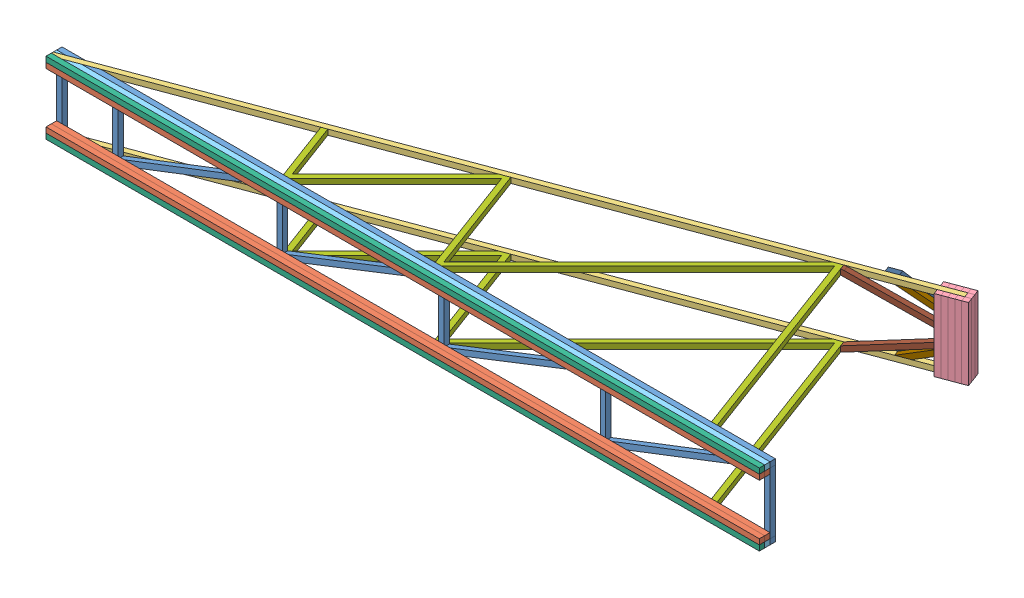
SolidWorks assembly boomAssembly2_1, configuration Default. Lengths in mm.
Overall size (423.17 42.7 155.97).
28 component instances, 12 part files, 91 mates.
Components (placement in the parent):
- cross brace compression-3: cross brace compression [Default] at (-109.2004 207.2528 347.8228) size (423.18 42.7 3.17)
- Part1-1: Part1 [Default] at (-109.2004 207.2528 354.1728) size (423.18 36.35 3.17)
- tension members-3: tension members [Default] at (269.1249 227.7278 350.9978) x (-1 0 0) z (0 0 1) size (396.18 3.18 148.71)
- tension members-4: tension members [Default] at (269.1249 267.2528 350.9978) x (-1 0 0) z (0 0 1) size (396.18 3.18 148.71)
- jHookMount-1: jHookMount [Default] at (264.7186 215.9028 209.7497) x (0.936777 0 -0.349926) z (0 1 0) size (3.17 3.17 42.7)
- jHookMount-2: jHookMount [Default] at (266.9407 215.9028 215.6982) x (0.936777 0 -0.349926) z (0 1 0) size (3.17 3.17 42.7)
- Part1^boomAssembly2_1-1: Part1^boomAssembly2_1 [Default] at origin (virtual)
- Part2^boomAssembly2_1-1: Part2^boomAssembly2_1 [Default] at (269.1249 258.6028 350.9978) x (1 0 0) z (0 1 0) size (423.17 3.17 3.17) (virtual)
- Part1-2: Part1 [Default] at (-109.2004 207.2528 357.3478) size (423.18 36.35 3.17)
- Part3^boomAssembly2_1-1: Part3^boomAssembly2_1 [Default] at (-127.3754 207.2528 357.3478) x (0 0 1) z (-1 0 0) size (3.17 42.7 423.18) (virtual)
- Part4^boomAssembly2_1-1: Part4^boomAssembly2_1 [Default] at (269.1249 258.6028 350.9978) x (1 0 0) z (0 1 0) size (270.59 119.85 3.17) (virtual)
- Part2^boomAssembly2_1-2: Part2^boomAssembly2_1 [Default] at (269.1249 219.0778 350.9978) x (1 0 0) z (0 1 0) size (423.17 3.17 3.17) (virtual)
- Part4^boomAssembly2_1-2: Part4^boomAssembly2_1 [Default] at (269.1249 219.0778 350.9978) x (1 0 0) z (0 1 0) size (270.59 119.85 3.17) (virtual)
- jHookMount-8: jHookMount [Default] at (261.7444 215.9028 210.8607) x (0.936777 0 -0.349926) z (0 1 0) size (3.17 3.17 42.7)
- jHookMount-9: jHookMount [Default] at (265.8296 215.9028 212.724) x (-0.936777 0 0.349926) z (0 1 0) size (3.17 3.17 42.7)
- jHookMount-10: jHookMount [Default] at (258.7701 215.9028 211.9717) x (0.936777 0 -0.349926) z (0 1 0) size (3.17 3.17 42.7)
- jHookMount-11: jHookMount [Default] at (260.9921 215.9028 217.9203) x (0.936777 0 -0.349926) z (0 1 0) size (3.17 3.17 42.7)
- Part5^boomAssembly2_1-1: Part5^boomAssembly2_1 [Default] at (267.6929 215.9028 208.6387) x (0 -1 0) z (0.936777 0 -0.349926) size (36.35 3.17 3.17) (virtual)
- Part5^boomAssembly2_1-2: Part5^boomAssembly2_1 [Default] at (264.7186 215.9028 209.7497) x (0 -1 0) z (0.936777 0 -0.349926) size (36.35 3.17 3.17) (virtual)
- Part5^boomAssembly2_1-3: Part5^boomAssembly2_1 [Default] at (261.7444 215.9028 210.8607) x (0 -1 0) z (0.936777 0 -0.349926) size (36.35 3.17 3.17) (virtual)
- jHookMount-12: jHookMount [Default] at (268.8039 215.9028 211.6129) x (0.936777 0 -0.349926) z (0 1 0) size (3.17 3.17 42.7)
- jHookMount-13: jHookMount [Default] at (267.6929 215.9028 208.6387) x (0.936777 0 -0.349926) z (0 1 0) size (3.17 3.17 42.7)
- jHookMount-14: jHookMount [Default] at (269.9119 215.9028 214.5791) x (0.936777 0 -0.349926) z (0 1 0) size (3.17 3.17 42.7)
- Part6^boomAssembly2_1-1: Part6^boomAssembly2_1 [Default] at (222.2837 227.7278 225.6009) x (0.936777 0 -0.349926) z (-0.349926 0 -0.936777) size (22.84 36.35 3.17) (virtual)
- jHookMount-16: jHookMount [Default] at (258.0179 215.9028 219.0313) x (0.936777 0 -0.349926) z (0 1 0) size (3.17 3.17 42.7)
- jHookMount-17: jHookMount [Default] at (255.7958 215.9028 213.0827) x (0.936777 0 -0.349926) z (0 1 0) size (3.17 3.17 42.7)
- Part7^boomAssembly2_1-1: Part7^boomAssembly2_1 [Default] at (222.2837 227.7278 225.6009) x (0.936777 0 -0.349926) z (-0.349926 0 -0.936777) size (25.51 42.7 3.17) (virtual)
- Part9^boomAssembly2_1-1: Part9^boomAssembly2_1 [Default] at (223.3948 267.2528 228.5752) x (-0.936777 0 0.349926) z (0.349926 0 0.936777) size (43.13 42.7 3.17) (virtual)
Mates (geometry in assembly coordinates):
- Coincident4: coincident: plane of cross brace compression-3 through (-127.3754 207.2528 350.9978) normal (-1 0 0); plane of Part1-1 through (-127.3754 207.2528 357.3478) normal (-1 0 0)
- Coincident5: coincident: plane of cross brace compression-3 through (-109.2004 207.2528 354.1728) normal (0 0 1); plane of Part1-1 through (-109.2004 207.2528 354.1728) normal (0 0 -1)
- Coincident7: coincident: plane of Part1-1 through (-109.2004 207.2528 357.3478) normal (0 0 1); plane of tension members-3 through (291.79 227.7278 357.3478) normal (0 0 1)
- Coincident8: coincident: plane of cross brace compression-3 through (-107.5644 219.0778 352.2026) normal (-0.349926 0 -0.936777); plane of tension members-3 through (223.3948 176.3778 228.5752) normal (0.349926 0 0.936777)
- Coincident9: coincident: plane of Part1-1 through (-109.2004 219.0778 357.3478) normal (0 -1 0); plane of tension members-3 through (291.79 219.0778 350.9978) normal (0 1 0)
- Coincident10: coincident: plane of cross brace compression-3 through (-108.6754 255.4278 349.2284) normal (0.349926 0 0.936777); plane of tension members-4 through (222.2837 215.9028 225.6009) normal (-0.349926 0 -0.936777)
- Coincident11: coincident: plane of Part1-1 through (-109.2004 207.2528 357.3478) normal (0 0 1); plane of tension members-4 through (291.79 267.2528 357.3478) normal (0 0 1)
- Coincident12: coincident: plane of cross brace compression-3 through (-131.8656 258.6028 347.8228) normal (0 1 0); plane of tension members-4 through (291.79 258.6028 350.9978) normal (0 1 0)
- Coincident13: coincident: plane of cross brace compression-3 through (-131.8656 219.0778 347.8228) normal (0 1 0); plane of Part1-1 through (-109.2004 219.0778 357.3478) normal (0 -1 0)
- Coincident14: coincident: plane of tension members-3 through (222.2837 176.3778 225.6009) normal (-0.349926 0 -0.936777); plane of jHookMount-1 through (264.7186 258.6028 209.7497) normal (0.349926 0 0.936777)
- Coincident15: coincident: plane of tension members-4 through (291.79 258.6028 350.9978) normal (0 1 0); plane of jHookMount-1 through (264.7186 258.6028 209.7497) normal (0 1 0)
- Coincident17: coincident: plane of tension members-3 through (223.3948 176.3778 228.5752) normal (0.349926 0 0.936777); plane of jHookMount-2 through (265.8296 258.6028 212.724) normal (-0.349926 0 -0.936777)
- Coincident19: coincident: plane of tension members-3 through (291.79 215.9028 350.9978) normal (0 -1 0); plane of jHookMount-2 through (266.9407 215.9028 215.6982) normal (0 -1 0)
- InPlace1: in place: plane of tension members-4 through (291.79 258.6028 350.9978) normal (0 1 0); plane of ? through (0 258.6028 0) normal (0 1 0); moOrthogonalPlaneRef_w of tension members-4 through (291.79 258.6028 350.9978) normal (0 1 0); plane of ? through (0 258.6028 0) normal (0 0 -1); plane of tension members-4 through (291.79 258.6028 350.9978) normal (0 1 0); plane of ? through (0 258.6028 0) normal (1 0 0); plane of tension members-4 through (291.79 258.6028 350.9978) normal (0 1 0); unknown of ?
- Coincident20: coincident: plane of tension members-4; plane of Part2^boomAssembly2_1-1
- Coincident21: coincident: moOrthogonalPlaneRef_w of tension members-4 through (269.1249 258.6028 350.9978) normal (0 0 -1); plane of Part2^boomAssembly2_1-1 through (269.1249 258.6028 350.9978) normal (0 0 -1)
- Coincident22: coincident: moOrthogonalPlaneRef_w of tension members-4 through (269.1249 258.6028 350.9978) normal (-1 0 0); plane of Part2^boomAssembly2_1-1 through (269.1249 258.6028 350.9978) normal (1 0 0)
- Coincident23: coincident: plane of Part1-1 through (-109.2004 222.2528 357.3478) normal (0 1 0); plane of Part1-2 through (-109.2004 222.2528 360.5228) normal (0 1 0)
- Coincident24: coincident: plane of Part1-1 through (-109.2004 207.2528 357.3478) normal (0 0 1); plane of Part1-2 through (-109.2004 207.2528 357.3478) normal (0 0 -1)
- Coincident25: coincident: plane of cross brace compression-3 through (-127.3754 207.2528 350.9978) normal (-1 0 0); plane of Part1-2 through (-127.3754 207.2528 360.5228) normal (-1 0 0)
- InPlace2: in place: plane of Part1-2 through (-127.3754 207.2528 360.5228) normal (-1 0 0); plane of ? through (-127.3754 0 0) normal (-1 0 0); plane of Part1-2 through (-127.3754 207.2528 360.5228) normal (-1 0 0); plane of ? through (-127.3754 0 0) normal (0 1 0); plane of Part1-2 through (-127.3754 207.2528 360.5228) normal (-1 0 0); plane of ? through (-127.3754 0 0) normal (0 0 1); plane of Part1-2 through (-127.3754 207.2528 360.5228) normal (-1 0 0); unknown of Part3^boomAssembly2_1-1
- Coincident26: coincident: plane of Part1-2; plane of Part3^boomAssembly2_1-1
- Coincident27: coincident: moOrthogonalPlaneRef_w of Part1-2 through (-127.3754 207.2528 357.3478) normal (0 1 0); plane of Part3^boomAssembly2_1-1 through (-127.3754 207.2528 357.3478) normal (0 1 0)
- Coincident28: coincident: moOrthogonalPlaneRef_w of Part1-2 through (-127.3754 207.2528 357.3478) normal (0 0 -1); plane of Part3^boomAssembly2_1-1 through (-127.3754 207.2528 357.3478) normal (0 0 1)
- InPlace3: in place: plane of tension members-4 through (291.79 258.6028 350.9978) normal (0 1 0); plane of ? through (0 258.6028 0) normal (0 1 0); plane of tension members-4 through (291.79 258.6028 350.9978) normal (0 1 0); plane of ? through (0 258.6028 0) normal (0 0 -1); plane of tension members-4 through (291.79 258.6028 350.9978) normal (0 1 0); plane of ? through (0 258.6028 0) normal (1 0 0); plane of tension members-4 through (291.79 258.6028 350.9978) normal (0 1 0); unknown of ?
- Coincident29: coincident: plane of tension members-4; plane of Part4^boomAssembly2_1-1
- Coincident30: coincident: moOrthogonalPlaneRef_w of tension members-4 through (269.1249 258.6028 350.9978) normal (0 0 -1); plane of Part4^boomAssembly2_1-1 through (269.1249 258.6028 350.9978) normal (0 0 -1)
- Coincident31: coincident: moOrthogonalPlaneRef_w of tension members-4 through (269.1249 258.6028 350.9978) normal (-1 0 0); plane of Part4^boomAssembly2_1-1 through (269.1249 258.6028 350.9978) normal (1 0 0)
- Coincident32: coincident: plane of tension members-4 through (314.534 267.2528 334.0356) normal (0.936777 0 -0.349926); plane of jHookMount-1 through (267.6929 258.6028 208.6387) normal (0.936777 0 -0.349926)
- Coincident33: coincident: plane of tension members-4 through (314.534 267.2528 334.0356) normal (0.936777 0 -0.349926); plane of jHookMount-2 through (269.9149 258.6028 214.5872) normal (0.936777 0 -0.349926)
- Coincident34: coincident: plane of tension members-4 through (223.3948 215.9028 228.5752) normal (0.349926 0 0.936777); plane of jHookMount-11 through (259.8811 258.6028 214.946) normal (-0.349926 0 -0.936777)
- Coincident35: coincident: plane of tension members-4 through (223.3948 215.9028 228.5752) normal (0.349926 0 0.936777); plane of jHookMount-9 through (265.8296 258.6028 212.724) normal (-0.349926 0 -0.936777)
- Coincident36: coincident: plane of tension members-3 through (291.79 215.9028 350.9978) normal (0 -1 0); plane of jHookMount-9 through (265.8296 215.9028 212.724) normal (0 -1 0)
- Coincident37: coincident: plane of tension members-3 through (291.79 215.9028 350.9978) normal (0 -1 0); plane of jHookMount-11 through (260.9921 215.9028 217.9203) normal (0 -1 0)
- Coincident38: coincident: plane of tension members-3 through (222.2837 176.3778 225.6009) normal (-0.349926 0 -0.936777); plane of jHookMount-8 through (261.7444 258.6028 210.8607) normal (0.349926 0 0.936777)
- Coincident39: coincident: plane of tension members-3 through (222.2837 176.3778 225.6009) normal (-0.349926 0 -0.936777); plane of jHookMount-10 through (258.7701 258.6028 211.9717) normal (0.349926 0 0.936777)
- Coincident40: coincident: plane of tension members-3 through (291.79 215.9028 350.9978) normal (0 -1 0); plane of jHookMount-8 through (261.7444 215.9028 210.8607) normal (0 -1 0)
- Coincident41: coincident: plane of tension members-3 through (291.79 215.9028 350.9978) normal (0 -1 0); plane of jHookMount-10 through (258.7701 215.9028 211.9717) normal (0 -1 0)
- Coincident42: coincident: plane of jHookMount-1 through (264.7186 258.6028 209.7497) normal (-0.936777 0 0.349926); plane of jHookMount-8 through (264.7186 258.6028 209.7497) normal (0.936777 0 -0.349926)
- Coincident43: coincident: plane of jHookMount-8 through (261.7444 258.6028 210.8607) normal (-0.936777 0 0.349926); plane of jHookMount-10 through (261.7444 258.6028 210.8607) normal (0.936777 0 -0.349926)
- Coincident44: coincident: plane of jHookMount-2 through (266.9407 258.6028 215.6982) normal (-0.936777 0 0.349926); plane of jHookMount-9 through (265.8296 258.6028 212.724) normal (0.936777 0 -0.349926)
- Coincident45: coincident: plane of jHookMount-9 through (262.8554 258.6028 213.835) normal (-0.936777 0 0.349926); plane of jHookMount-11 through (263.9664 258.6028 216.8092) normal (0.936777 0 -0.349926)
- InPlace4: in place: plane of jHookMount-8 through (264.7186 258.6028 209.7497) normal (0.936777 0 -0.349926); plane of ? through (163.5476 0 -61.092) normal (0.936777 0 -0.349926); plane of jHookMount-8 through (264.7186 258.6028 209.7497) normal (0.936777 0 -0.349926); plane of ? through (163.5476 0 -61.092) normal (0 1 0); plane of jHookMount-8 through (264.7186 258.6028 209.7497) normal (0.936777 0 -0.349926); plane of ? through (163.5476 0 -61.092) normal (-0.349926 0 -0.936777); plane of jHookMount-1 through (267.6929 258.6028 208.6387) normal (0.936777 0 -0.349926); unknown of Part5^boomAssembly2_1-1
- Coincident46: coincident: plane of jHookMount-1; plane of Part5^boomAssembly2_1-1
- Coincident47: coincident: moOrthogonalPlaneRef_w of jHookMount-1 through (267.6929 215.9028 208.6387) normal (-0.349926 0 -0.936777); plane of Part5^boomAssembly2_1-1 through (267.6929 215.9028 208.6387) normal (-0.349926 0 -0.936777)
- Coincident48: coincident: moOrthogonalPlaneRef_w of jHookMount-1 through (267.6929 215.9028 208.6387) normal (0 1 0); plane of Part5^boomAssembly2_1-1 through (267.6929 215.9028 208.6387) normal (0 -1 0)
- Coincident49: coincident: plane of tension members-4 through (291.79 255.4278 350.9978) normal (0 -1 0); plane of Part5^boomAssembly2_1-2 through (261.7444 255.4278 210.8607) normal (0 1 0)
- Coincident50: coincident: plane of Part5^boomAssembly2_1-1 through (264.7186 215.9028 209.7497) normal (-0.936777 0 0.349926); plane of Part5^boomAssembly2_1-2 through (264.7186 215.9028 209.7497) normal (0.936777 0 -0.349926)
- Coincident51: coincident: plane of jHookMount-8 through (261.7444 258.6028 210.8607) normal (0.349926 0 0.936777); plane of Part5^boomAssembly2_1-2 through (261.7444 255.4278 210.8607) normal (-0.349926 0 -0.936777)
- Coincident52: coincident: plane of jHookMount-10 through (258.7701 258.6028 211.9717) normal (0.349926 0 0.936777); plane of Part5^boomAssembly2_1-3 through (258.7701 255.4278 211.9717) normal (-0.349926 0 -0.936777)
- Coincident53: coincident: plane of tension members-4 through (291.79 255.4278 350.9978) normal (0 -1 0); plane of Part5^boomAssembly2_1-3 through (258.7701 255.4278 211.9717) normal (0 1 0)
- Coincident54: coincident: plane of Part5^boomAssembly2_1-2 through (261.7444 215.9028 210.8607) normal (-0.936777 0 0.349926); plane of Part5^boomAssembly2_1-3 through (261.7444 215.9028 210.8607) normal (0.936777 0 -0.349926)
- Coincident55: coincident: plane of jHookMount-2 through (266.9407 258.6028 215.6982) normal (0.936777 0 -0.349926); plane of ? through (265.8296 212.7278 212.724) normal (-0.936777 0 0.349926)
- Coincident56: coincident: plane of tension members-3 through (223.3948 176.3778 228.5752) normal (0.349926 0 0.936777); plane of ? through (265.8296 252.2528 212.724) normal (-0.349926 0 -0.936777)
- Coincident57: coincident: plane of jHookMount-2 through (263.9664 215.9028 216.8092) normal (0 -1 0); plane of ? through (265.8296 215.9028 212.724) normal (0 -1 0)
- Coincident58: coincident: plane of Part5^boomAssembly2_1-1 through (267.6929 215.9028 208.6387) normal (0.936777 0 -0.349926); plane of ? through (267.6929 215.9028 208.6387) normal (-0.936777 0 0.349926)
- Coincident59: coincident: plane of tension members-3 through (291.79 219.0778 350.9978) normal (0 1 0); plane of ? through (267.6929 219.0778 208.6387) normal (0 -1 0)
- Coincident60: coincident: plane of tension members-3 through (222.2837 176.3778 225.6009) normal (-0.349926 0 -0.936777); plane of ? through (267.6929 255.4278 208.6387) normal (-0.349926 0 -0.936777)
- Coincident61: coincident: plane of tension members-3 through (291.79 215.9028 350.9978) normal (0 -1 0); plane of jHookMount-12 through (268.8039 215.9028 211.6129) normal (0 -1 0)
- Coincident62: coincident: plane of Part5^boomAssembly2_1-1 through (267.6929 215.9028 208.6387) normal (0.936777 0 -0.349926); plane of jHookMount-12 through (268.8039 258.6028 211.6129) normal (-0.936777 0 0.349926)
- Coincident63: coincident: plane of tension members-3 through (222.2837 176.3778 225.6009) normal (-0.349926 0 -0.936777); plane of jHookMount-12 through (267.6929 258.6028 208.6387) normal (-0.349926 0 -0.936777)
- Coincident64: coincident: plane of jHookMount-12 through (271.7782 258.6028 210.5019) normal (0.936777 0 -0.349926); plane of jHookMount-13 through (270.6672 258.6028 207.5277) normal (0.936777 0 -0.349926)
- Coincident65: coincident: plane of jHookMount-12 through (271.7782 258.6028 210.5019) normal (0.936777 0 -0.349926); plane of jHookMount-14 through (272.8862 258.6028 213.4681) normal (0.936777 0 -0.349926)
- Coincident66: coincident: plane of jHookMount-12 through (268.8039 215.9028 211.6129) normal (0 -1 0); plane of jHookMount-13 through (267.6929 215.9028 208.6387) normal (0 -1 0)
- Coincident67: coincident: plane of jHookMount-12 through (268.8039 215.9028 211.6129) normal (0 -1 0); plane of jHookMount-14 through (269.9119 215.9028 214.5791) normal (0 -1 0)
- Coincident68: coincident: plane of jHookMount-12 through (267.6929 258.6028 208.6387) normal (-0.349926 0 -0.936777); plane of jHookMount-13 through (267.6929 258.6028 208.6387) normal (0.349926 0 0.936777)
- InPlace5: in place: plane of tension members-3 through (222.2837 176.3778 225.6009) normal (-0.349926 0 -0.936777); plane of ? through (101.171 0 270.8417) normal (-0.349926 0 -0.936777); plane of tension members-3 through (222.2837 176.3778 225.6009) normal (-0.349926 0 -0.936777); plane of ? through (101.171 0 270.8417) normal (0 1 0); plane of tension members-3 through (222.2837 176.3778 225.6009) normal (-0.349926 0 -0.936777); plane of ? through (101.171 0 270.8417) normal (-0.936777 0 0.349926); plane of tension members-3 through (222.2837 176.3778 225.6009) normal (-0.349926 0 -0.936777); unknown of ?
- Coincident69: coincident: plane of tension members-3; plane of Part6^boomAssembly2_1-1
- Coincident70: coincident: moOrthogonalPlaneRef_w of tension members-3 through (222.2837 227.7278 225.6009) normal (0 -1 0); plane of Part6^boomAssembly2_1-1 through (222.2837 227.7278 225.6009) normal (0 -1 0)
- Coincident71: coincident: moOrthogonalPlaneRef_w of tension members-3 through (222.2837 227.7278 225.6009) normal (-0.936777 0 0.349926); plane of Part6^boomAssembly2_1-1 through (222.2837 227.7278 225.6009) normal (0.936777 0 -0.349926)
- Coincident72: coincident: plane of Part6^boomAssembly2_1-1 through (223.3948 215.9028 228.5752) normal (0.349926 0 0.936777); plane of jHookMount-16 through (256.9068 258.6028 216.057) normal (-0.349926 0 -0.936777)
- Coincident73: coincident: plane of tension members-3 through (222.2837 176.3778 225.6009) normal (-0.349926 0 -0.936777); plane of jHookMount-17 through (255.7958 258.6028 213.0827) normal (0.349926 0 0.936777)
- Coincident74: coincident: plane of jHookMount-11 through (260.9921 215.9028 217.9203) normal (0 -1 0); plane of jHookMount-16 through (258.0179 215.9028 219.0313) normal (0 -1 0)
- Coincident75: coincident: plane of tension members-3 through (291.79 215.9028 350.9978) normal (0 -1 0); plane of jHookMount-17 through (255.7958 215.9028 213.0827) normal (0 -1 0)
- Coincident76: coincident: plane of jHookMount-10 through (258.7701 258.6028 211.9717) normal (-0.936777 0 0.349926); plane of jHookMount-17 through (258.7701 258.6028 211.9717) normal (0.936777 0 -0.349926)
- Coincident77: coincident: plane of jHookMount-11 through (260.9921 258.6028 217.9203) normal (-0.936777 0 0.349926); plane of jHookMount-16 through (260.9921 258.6028 217.9203) normal (0.936777 0 -0.349926)
- InPlace6: in place: plane of tension members-3 through (222.2837 176.3778 225.6009) normal (-0.349926 0 -0.936777); plane of ? through (101.171 0 270.8417) normal (-0.349926 0 -0.936777); plane of tension members-3 through (222.2837 176.3778 225.6009) normal (-0.349926 0 -0.936777); plane of ? through (101.171 0 270.8417) normal (0 1 0); plane of tension members-3 through (222.2837 176.3778 225.6009) normal (-0.349926 0 -0.936777); plane of ? through (101.171 0 270.8417) normal (-0.936777 0 0.349926); plane of tension members-3 through (222.2837 176.3778 225.6009) normal (-0.349926 0 -0.936777); unknown of ?
- Coincident78: coincident: plane of tension members-3; plane of Part7^boomAssembly2_1-1
- Coincident79: coincident: moOrthogonalPlaneRef_w of tension members-3 through (222.2837 227.7278 225.6009) normal (0 -1 0); plane of Part7^boomAssembly2_1-1 through (222.2837 227.7278 225.6009) normal (0 -1 0)
- Coincident80: coincident: moOrthogonalPlaneRef_w of tension members-3 through (222.2837 227.7278 225.6009) normal (-0.936777 0 0.349926); plane of Part7^boomAssembly2_1-1 through (222.2837 227.7278 225.6009) normal (0.936777 0 -0.349926)
- Coincident81: coincident: plane of jHookMount-16 through (258.0179 258.6028 219.0313) normal (-0.936777 0 0.349926); plane of ? through (256.9068 229.7528 216.057) normal (0.936777 0 -0.349926)
- Coincident82: coincident: plane of tension members-3 through (291.79 215.9028 350.9978) normal (0 -1 0); plane of ? through (233.0113 215.9028 224.983) normal (0 -1 0)
- Coincident83: coincident: plane of tension members-3 through (223.3948 176.3778 228.5752) normal (0.349926 0 0.936777); plane of ? through (223.3948 227.7278 228.5752) normal (-0.349926 0 -0.936777)
- InPlace7: in place: plane of tension members-4 through (223.3948 215.9028 228.5752) normal (0.349926 0 0.936777); plane of ? through (102.282 0 273.816) normal (0.349926 0 0.936777); plane of tension members-4 through (223.3948 215.9028 228.5752) normal (0.349926 0 0.936777); plane of ? through (102.282 0 273.816) normal (0 1 0); plane of tension members-4 through (223.3948 215.9028 228.5752) normal (0.349926 0 0.936777); plane of ? through (102.282 0 273.816) normal (0.936777 0 -0.349926); plane of tension members-4 through (223.3948 215.9028 228.5752) normal (0.349926 0 0.936777); unknown of Part9^boomAssembly2_1-1
- Coincident84: coincident: plane of tension members-4; plane of ?
- Coincident85: coincident: moOrthogonalPlaneRef_w of tension members-4 through (223.3948 267.2528 228.5752) normal (0 -1 0); plane of Part9^boomAssembly2_1-1 through (223.3948 267.2528 228.5752) normal (0 -1 0)
- Coincident86: coincident: moOrthogonalPlaneRef_w of tension members-4 through (223.3948 267.2528 228.5752) normal (0.936777 0 -0.349926); plane of Part9^boomAssembly2_1-1 through (223.3948 267.2528 228.5752) normal (-0.936777 0 0.349926)
- InPlace8: in place: plane of tension members-4 through (223.3948 215.9028 228.5752) normal (0.349926 0 0.936777); plane of ? through (102.282 0 273.816) normal (0.349926 0 0.936777); plane of tension members-4 through (223.3948 215.9028 228.5752) normal (0.349926 0 0.936777); plane of ? through (102.282 0 273.816) normal (0 1 0); plane of tension members-4 through (223.3948 215.9028 228.5752) normal (0.349926 0 0.936777); plane of ? through (102.282 0 273.816) normal (0.936777 0 -0.349926); plane of tension members-4 through (223.3948 215.9028 228.5752) normal (0.349926 0 0.936777); unknown of Part9^boomAssembly2_1-1
- Coincident87: coincident: plane of tension members-4; plane of Part9^boomAssembly2_1-1
- Coincident88: coincident: moOrthogonalPlaneRef_w of tension members-4 through (223.3948 267.2528 228.5752) normal (0 -1 0); plane of Part9^boomAssembly2_1-1 through (223.3948 267.2528 228.5752) normal (0 -1 0)
- Coincident89: coincident: moOrthogonalPlaneRef_w of tension members-4 through (223.3948 267.2528 228.5752) normal (0.936777 0 -0.349926); plane of Part9^boomAssembly2_1-1 through (223.3948 267.2528 228.5752) normal (-0.936777 0 0.349926)
